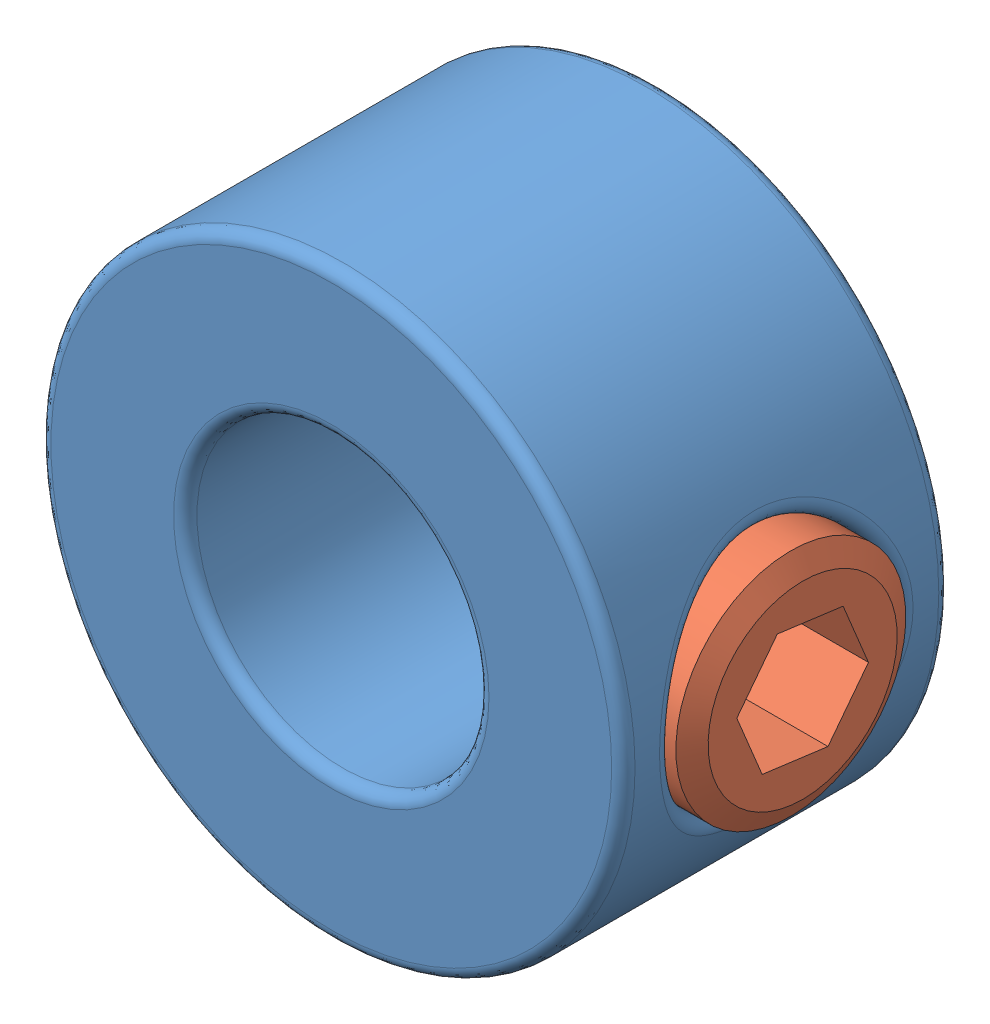
SolidWorks assembly Assem4, configuration Default. Lengths in mm.
Overall size (13.05 12.7 7.11).
2 component instances, 2 part files, 2 mates.
Components (placement in the parent):
- Lock Collar .25 inch-1: Lock Collar .25 inch [Default] at (2.1859 6.4507 11.2166) size (12.7 12.7 7.11)
- Socket Set Screw Cup Point_AM-2: Socket Set Screw Cup Point_AM [B18.3.6M - M5 x 0.8 x 4 Hex Socket Type I Cup Pt. SS --N] at (8.89 6.4507 14.7853) x (-1 0 0) z (0 -0.924225 -0.381849) size (4 5 5)
Mates (geometry in assembly coordinates):
- Concentric1: concentric anti-aligned: cylinder of Lock Collar .25 inch-1 through (21.2359 6.4507 14.7853) axis (-1 0 0) radius 2.5; cylinder of Socket Set Screw Cup Point_AM-2 through (21.59 6.4507 14.7853) axis (1 0 0) radius 2.5
- Distance1: distance = 8.89 mm aligned: plane of assembly through (0 0 0) normal (1 0 0); plane of Socket Set Screw Cup Point_AM-2 through (8.89 6.4507 14.7853) normal (1 0 0)
